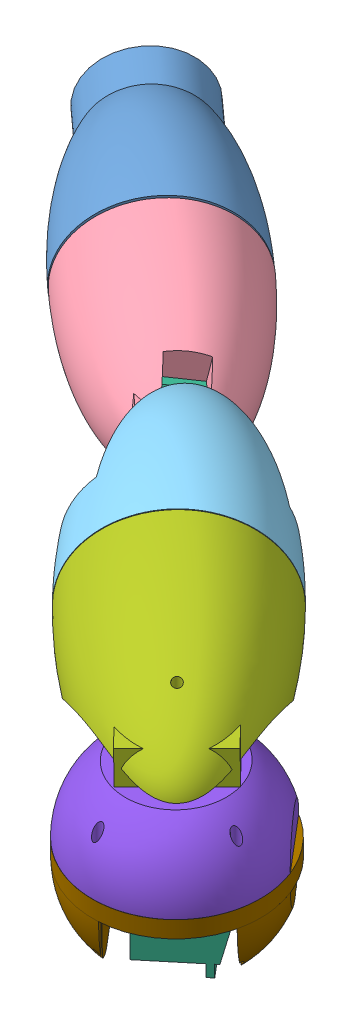
SolidWorks assembly Main-01, configuration Default. Lengths in mm.
Overall size (406.26 208.17 397.69).
21 component instances, 9 part files, 29 mates.
Components (placement in the parent):
- Part-Lower-2-1: Part-Lower-2 [Default] at (-264.2785 -79.8342 50.4233) x (-0.63082 -0.443183 0.63691) z (-0.742679 0.107149 -0.66102) size (90 90 220)
- Servo-01-1: Servo-01 [Default] at (-210.171 -11.0025 91.7663) x (0.638491 -0.184288 -0.74724) z (-0.742679 0.107149 -0.66102) size (27.63 54.2 54.1)
  - Servo-Body-2: Servo-Body [Default] at (17.7434 12.3164 23.3438) size (20.01 54.2 54.1)
  - Servo-Horn-2: Servo-Horn [Default] at (17.7434 12.3164 75.4438) x (-0.842157 -0.539233 0) z (0 0 1) size (20 20 5.5)
- Part-Lower-1-3: Part-Lower-1 [Default] at (-265.1938 32.4864 70.5022) x (-0.638491 0.184288 0.74724) z (0.742679 -0.107149 0.66102) size (90 90 141.99)
- Part-Upper-2-1: Part-Upper-2 [Default] at (-55.2914 3.8937 137.7746) x (0.687341 -0.191124 -0.700738) z (-0.697714 0.094417 -0.710127) size (100 99.78 127.75)
- Servo-02-1: Servo-02 [Default] at (-157.9727 -69.8391 138.2317) x (0.638491 -0.184288 -0.74724) z (0.201884 0.977014 -0.068453) size (20.01 54.2 48.1)
  - Servo-Body-6mm-1: Servo-Body-6mm [Default] at (8.2932 21.7501 21.9215) size (20.01 54.2 48.1)
  - Servo-Horn-1: Servo-Horn [Default] at (8.2932 21.7501 68.0215) size (20 20 5.5)
- Part-Upper-1-1: Part-Upper-1 [Left] at (-106.5403 -84.4354 167.7389) x (0.713817 0.007913 -0.700287) z (0.697714 -0.094417 0.710127) size (139.94 103.76 247.91)
- Servo-01-4: Servo-01 [Default] at (-68.3486 -58.5774 225.5295) x (0.0605 0.995501 0.072917) z (-0.697714 0.094417 -0.710127) size (27.63 54.2 54.1)
  - Servo-Body-2: Servo-Body [Default] at (17.7434 12.3164 23.3438) size (20.01 54.2 54.1)
  - Servo-Horn-2: Servo-Horn [Default] at (17.7434 12.3164 75.4438) x (-0.842157 -0.539233 0) z (0 0 1) size (20 20 5.5)
- Part-Shoulder-2-1: Part-Shoulder-2 [Left] at (99.5675 -94.0409 181.487) x (0.769593 0 -0.638535) z (0.0605 0.995501 0.072917) size (102.82 104.93 50.48)
- Servo-02-2: Servo-02 [Default] at (-35.1284 -113.2929 255.4475) x (0.769593 0 -0.638535) z (0.0605 0.995501 0.072917) size (20.01 54.2 48.1)
  - Servo-Body-6mm-1: Servo-Body-6mm [Default] at (8.2932 21.7501 21.9215) size (20.01 54.2 48.1)
  - Servo-Horn-1: Servo-Horn [Default] at (8.2932 21.7501 68.0215) size (20 20 5.5)
- Part-Shoulder-1-1: Part-Shoulder-1 [Left] at (32.887 -97.3929 301.9861) x (-0.769593 0 0.638535) z (-0.0605 -0.995501 -0.072917) size (102.75 100 51.7)
- Servo-02-3: Servo-02 [Default] at (-81.5232 -96.3556 250.7473) x (0.63632 -0.083212 0.766924) z (0.769593 0 -0.638535) size (20.01 54.2 48.1)
  - Servo-Body-6mm-1: Servo-Body-6mm [Default] at (8.2932 21.7501 21.9215) size (20.01 54.2 48.1)
  - Servo-Horn-1: Servo-Horn [Default] at (8.2932 21.7501 68.0215) size (20 20 5.5)
Mates (geometry in assembly coordinates):
- Coincident9: coincident anti-aligned: plane of Servo-01-1/Servo-Body-2 through (-225.0503 -21.9615 71.3925) normal (-0.638491 0.184288 0.74724); plane of Part-Lower-1-3 through (-231.9844 -48.116 71.918) normal (0.638491 -0.184288 -0.74724)
- Coincident10: coincident anti-aligned: plane of Servo-01-1/Servo-Body-2 through (-230.9815 -50.6654 73.4036) normal (-0.201884 -0.977014 0.068453); plane of Part-Lower-1-3 through (-219.0585 -54.3211 56.3896) normal (0.201884 0.977014 -0.068453)
- Coincident12: coincident anti-aligned: plane of Servo-01-1/Servo-Body-2 through (-258.3149 -45.9925 59.4867) normal (0.742679 -0.107149 0.66102); plane of Part-Lower-1-3 through (-260.5623 31.8182 74.6245) normal (-0.742679 0.107149 -0.66102)
- Coincident13: coincident anti-aligned: plane of Servo-01-1/Servo-Body-2 through (-259.7482 -52.9293 59.9727) normal (-0.201884 -0.977014 0.068453); plane of Part-Lower-1-3 through (-278.1242 -50.9154 34.5217) normal (0.201884 0.977014 -0.068453)
- Coincident29: coincident anti-aligned: plane of Part-Lower-1-3 through (-153.0951 -3.1537 128.2374) normal (0.638491 -0.184288 -0.74724); plane of Servo-02-1/Servo-Body-6mm-1 through (-170.7902 -45.7765 123.6293) normal (-0.638491 0.184288 0.74724)
- Coincident30: coincident anti-aligned: plane of Part-Lower-1-3 through (-184.1834 1.4237 101.8828) normal (0.742679 -0.107149 0.66102); plane of Servo-02-1/Servo-Body-6mm-1 through (-192.6095 -42.6286 104.2091) normal (-0.742679 0.107149 -0.66102)
- Coincident31: coincident anti-aligned: plane of Part-Lower-1-3 through (-251.0552 -3.92 46.0611) normal (0.201884 0.977014 -0.068453); plane of Servo-02-1/Servo-Body-6mm-1 through (-156.8458 -17.6041 128.5963) normal (-0.201884 -0.977014 0.068453)
- Coincident36: coincident anti-aligned: plane of Part-Lower-2-1 through (-258.8444 -18.0077 28.159) normal (0.742679 -0.107149 0.66102); plane of Servo-01-1/Servo-Horn-2 through (-258.8444 -18.0077 28.159) normal (-0.742679 0.107149 -0.66102)
- Concentric4: concentric anti-aligned: cylinder of Part-Lower-2-1 through (-257.359 -18.222 29.481) axis (-0.742679 0.107149 -0.66102) radius 10; cylinder of Servo-01-1/Servo-Horn-2 through (-258.8444 -18.0077 28.159) axis (0.742679 -0.107149 0.66102) radius 10
- Coincident37: coincident anti-aligned: plane of Part-Upper-2-1 through (-146 -7.1977 44.6968) normal (-0.201884 -0.977014 0.068453); plane of Servo-02-1/Servo-Horn-1 through (-154.6947 -0.625 112.8643) normal (0.201884 0.977014 -0.068453)
- Concentric5: concentric anti-aligned: cylinder of Part-Upper-2-1 through (-155.0985 -2.579 113.0012) axis (0.201884 0.977014 -0.068453) radius 10; cylinder of Servo-02-1/Servo-Horn-1 through (-154.6947 -0.625 112.8643) axis (-0.201884 -0.977014 0.068453) radius 10
- Coincident42: coincident anti-aligned: plane of Part-Upper-1-1 through (-114.6111 -24.3045 176.4821) normal (-0.0605 -0.995501 -0.072917); plane of Servo-01-4/Servo-Body-2 through (-74.1658 -28.6572 202.3504) normal (0.0605 0.995501 0.072917)
- Coincident43: coincident anti-aligned: plane of Part-Upper-1-1 through (-115.8102 -45.2092 174.8808) normal (0.713817 0.007913 -0.700287); plane of Servo-01-4/Servo-Body-2 through (-82.9572 -48.6513 208.3297) normal (-0.713817 -0.007913 0.700287)
- Coincident44: coincident anti-aligned: plane of Part-Upper-1-1 through (-88.4362 -35.6992 173.1891) normal (-0.697714 0.094417 -0.710127); plane of Servo-01-4/Servo-Body-2 through (-103.8886 -45.8188 187.0259) normal (0.697714 -0.094417 0.710127)
- Coincident45: coincident anti-aligned: plane of Part-Upper-2-1 through (-112.5171 -33.5043 163.2033) normal (0.697714 -0.094417 0.710127); plane of Servo-01-4/Servo-Horn-2 through (-112.5171 -33.5043 163.2033) normal (-0.697714 0.094417 -0.710127)
- Concentric6: concentric anti-aligned: cylinder of Part-Upper-2-1 through (-111.1217 -33.6931 164.6236) axis (-0.697714 0.094417 -0.710127) radius 10; cylinder of Servo-01-4/Servo-Horn-2 through (-112.5171 -33.5043 163.2033) axis (0.697714 -0.094417 0.710127) radius 10
- Coincident49: coincident anti-aligned: plane of Part-Upper-1-1 through (-46.9013 -41.6206 246.9979) normal (-0.0605 -0.995501 -0.072917); plane of Servo-02-2/Servo-Horn-1 through (-38.3355 -41.5257 238.5944) normal (0.0605 0.995501 0.072917)
- Concentric7: concentric aligned: cylinder of Part-Upper-1-1 through (-38.275 -40.5302 238.6673) axis (-0.0605 -0.995501 -0.072917) radius 10; cylinder of Servo-02-2/Servo-Horn-1 through (-38.3355 -41.5257 238.5944) axis (-0.0605 -0.995501 -0.072917) radius 10
- Coincident50: coincident anti-aligned: plane of Part-Shoulder-2-1 through (-39.7395 -60.6453 252.5631) normal (0.769593 0 -0.638535); plane of Servo-02-2/Servo-Body-6mm-1 through (-48.9414 -89.4093 241.4724) normal (-0.769593 0 0.638535)
- Coincident51: coincident anti-aligned: plane of Part-Shoulder-2-1 through (-24.2137 -60.5505 238.3877) normal (-0.635662 0.094748 -0.766131); plane of Servo-02-2/Servo-Body-6mm-1 through (-42.1901 -90.4156 249.6094) normal (0.635662 -0.094748 0.766131)
- Coincident52: coincident anti-aligned: plane of Part-Shoulder-2-1 through (-38.9395 -58.3556 220.6395) normal (0.0605 0.995501 0.072917); plane of Servo-02-2/Servo-Body-6mm-1 through (-40.3751 -60.5505 251.7969) normal (-0.0605 -0.995501 -0.072917)
- Coincident58: coincident anti-aligned: plane of Part-Shoulder-2-1 through (-42.4123 -89.3035 234.6113) normal (-0.0605 -0.995501 -0.072917); plane of Part-Shoulder-1-1 through (-42.3983 -89.3138 234.7397) normal (0.0605 0.995501 0.072917)
- Coincident59: coincident aligned: plane of Part-Shoulder-2-1 through (28.1179 -54.2907 246.6472) normal (0.769593 0 -0.638535); plane of Part-Shoulder-1-1 through (22.6812 -143.7489 240.0947) normal (0.769593 0 -0.638535)
- Concentric11: concentric anti-aligned: cylinder of Part-Shoulder-2-1 through (-44.7348 -92.2158 276.2981) axis (-0.0605 -0.995501 -0.072917) radius 2.5; cylinder of Part-Shoulder-1-1 through (-45.3315 -102.0339 275.5789) axis (0.0605 0.995501 0.072917) radius 2.5
- Concentric12: concentric anti-aligned: cylinder of Part-Shoulder-2-1 through (-2.4072 -92.2158 241.1786) axis (-0.0605 -0.995501 -0.072917) radius 2.5; cylinder of Part-Shoulder-1-1 through (-5.535 -143.6829 237.4089) axis (0.0605 0.995501 0.072917) radius 2.5
- Concentric13: concentric anti-aligned: cylinder of Part-Shoulder-2-1 through (-43.7253 -86.0572 191.3802) axis (-0.0605 -0.995501 -0.072917) radius 2.5; cylinder of Part-Shoulder-1-1 through (-46.8531 -137.5242 187.6104) axis (0.0605 0.995501 0.072917) radius 2.5
- Concentric14: concentric anti-aligned: cylinder of Part-Shoulder-2-1 through (-86.0529 -86.0572 226.4996) axis (-0.0605 -0.995501 -0.072917) radius 2.5; cylinder of Part-Shoulder-1-1 through (-86.6495 -95.8753 225.7804) axis (0.0605 0.995501 0.072917) radius 2.5
- Coincident60: coincident anti-aligned: plane of Part-Shoulder-1-1 through (-25.4207 -118.4361 208.7051) normal (-0.769593 0 0.638535); plane of Servo-02-3/Servo-Horn-1 through (-23.5137 -118.7203 211.0035) normal (0.769593 0 -0.638535)
- Concentric15: concentric aligned: cylinder of Part-Shoulder-1-1 through (-25.0529 -118.7203 212.2805) axis (-0.769593 0 0.638535) radius 10; cylinder of Servo-02-3/Servo-Horn-1 through (-23.5137 -118.7203 211.0035) axis (-0.769593 0 0.638535) radius 10
